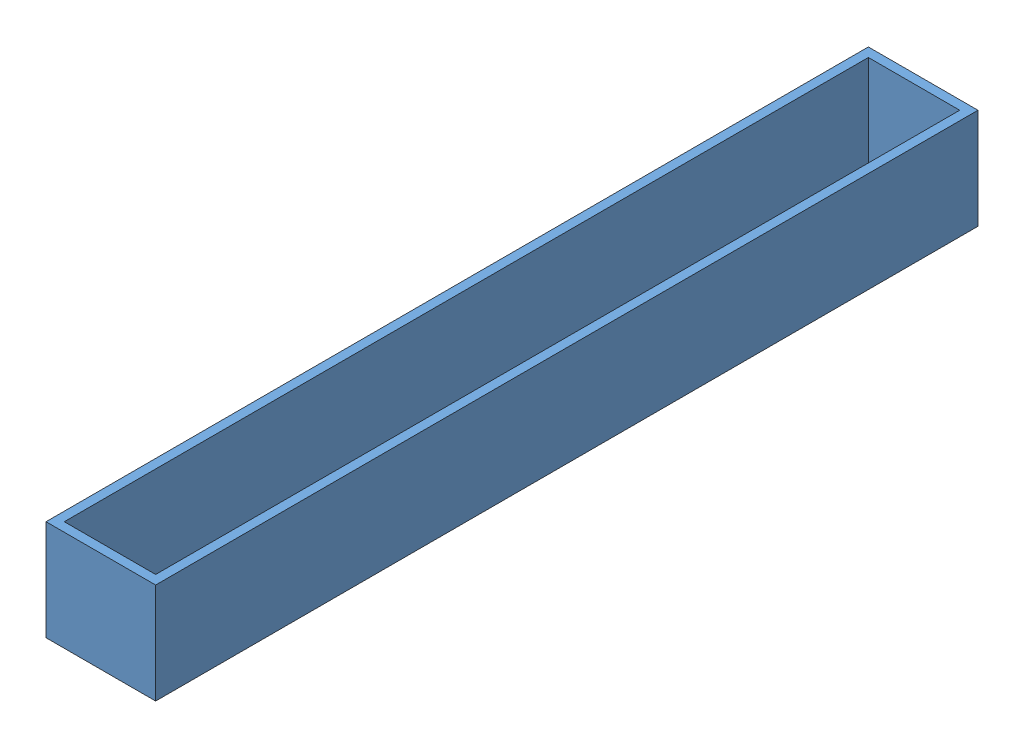
SolidWorks assembly Ensamblaje2, configuration Predeterminado. Lengths in mm.
Overall size (1200 1100 9000).
2 component instances, 2 part files, 3 mates.
Components (placement in the parent):
- trinchera de 9 metros-1: trinchera de 9 metros [Predeterminado] at (-6320.0364 7017.2897 -2363.6456) size (1200 1100 9000)
- charola para l5 6-1: charola para l5 6 [Predeterminado] at (-5905.4905 6988.2577 6636.3544) size (240 61.5 9000)
Mates (geometry in assembly coordinates):
- Coincidente1: coincident: plane of trinchera de 9 metros-1 through (-6320.0364 7017.2897 -2363.6456) normal (0 0 -1); plane of charola para l5 6-1 through (-5905.4905 7664.355 -2363.6456) normal (0 0 -1)
- Coincidente2: coincident: plane of trinchera de 9 metros-1 through (-5820.0364 6567.2897 -2263.6456) normal (-1 0 0); plane of charola para l5 6-1 through (-5820.0364 7704.8869 -2363.6456) normal (1 0 0)
- Coincidente3: coincident anti-aligned: plane of trinchera de 9 metros-1 through (-5825.0364 6967.2897 -2063.6456) normal (0 1 0); plane of charola para l5 6-1 through (-6042.0364 6967.2897 -2363.6456) normal (0 -1 0)
